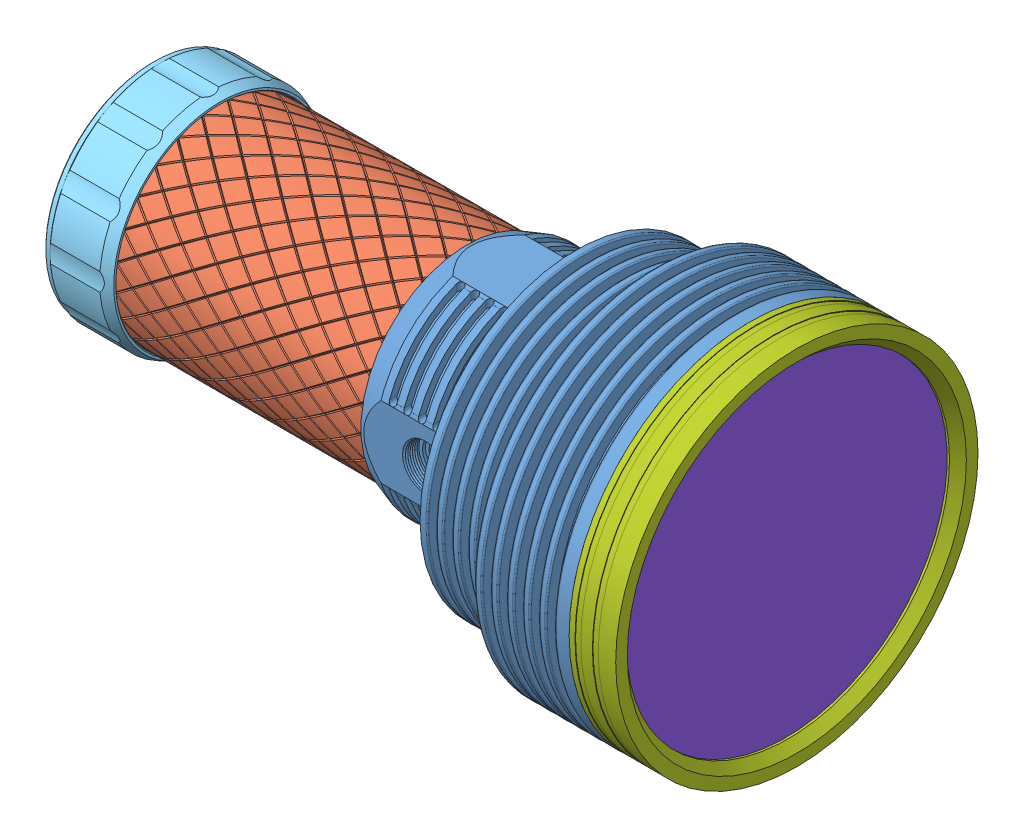
SolidWorks assembly 装配效果, configuration 默认. Lengths in mm.
Overall size (221.4 127.88 124.96).
271 component instances, 41 part files, 31 mates.
Components (placement in the parent):
- 筒头.stp-1: 筒头.stp [默认] at (76.9357 7.8194 125.8618) size (110.07 125.86 124.6)
- 筒身组件.stp-1: 筒身组件.stp [默认] at (-118.9643 -77.3753 22.2057) x (0 0 1) z (-1 0 0) size (71.18 73.16 116.38)
- 电池仓前盖.stp-1: 电池仓前盖.stp [默认] at (-20.4643 7.8194 125.8618) x (0 -1 0) z (1 0 0) size (68 69.4 6)
- 电池仓尾部显示面板.stp-1: 电池仓尾部显示面板.stp [默认] at (-9.4643 7.8194 125.8618) x (0 0 1) z (-1 0 0) size (66.2 66.2 8.5)
- 电池仓尾盖.stp-1: 电池仓尾盖.stp [默认] at (-119.4643 7.8194 125.8618) x (0 0 1) z (-1 0 0) size (76.61 76.61 23)
- SD12反光杯.stp-1: SD12反光杯.stp [默认] at (76.8857 7.8194 125.8618) size (60.57 118 118)
- 驱动仓玻璃压环.prt-1: 驱动仓玻璃压环.prt [默认] at (76.9357 7.8194 125.8618) size (18.46 127.88 124.96)
- 远射炮玻璃-1: 远射炮玻璃 [默认] at (80.8857 7.8194 125.8618) x (0 0 1) z (-1 0 0) size (118 118 4)
- 驱动压环.prt-1: 驱动压环.prt [默认] at (76.7354 7.8194 125.8618) size (7.5 56.14 54.2)
- LCD屏幕保护窗.step-1: LCD屏幕保护窗.step [默认] at (-17.9643 7.8194 125.8618) x (0 0 1) z (-1 0 0) size (26.1 15.2 2.5)
- 驱动.step-1: 驱动.step [默认] at (-8.5643 -72.1806 205.8618) x (0 0 -1) z (1 0 0) size (46.93 46.93 12.66)
  - U3.step-1: U3.step [默认] at origin size (3 1.4 1.05)
    - 549114896.step-1: 549114896.step [默认] at (69.342 72.263 -2.7003) size (3 1.4 1.05)
      - Extruded.step-1: Extruded.step [默认] at origin size (3 1.4 1.05)
  - C55.step-1: C55.step [默认] at origin size (1.6 0.8 0.3)
    - User_Library-0603_SMD_Capacitor.step-1: User_Library-0603_SMD_Capacitor.step [默认] at (69.342 69.469 -1.6003) x (-1 0 0) z (0 -1 0) size (1.6 0.3 0.8)
  - C54.step-1: C54.step [默认] at origin size (1.61 3.21 0.95)
    - User_Library-C_SMD_1206.step-1: User_Library-C_SMD_1206.step [默认] at (84.328 97.663 0) x (0 -1 0) z (0 0 1) size (3.21 1.61 0.95)
  - C53.step-1: C53.step [默认] at origin size (1.61 3.21 0.95)
    - User_Library-C_SMD_1206.step-1: User_Library-C_SMD_1206.step [默认] at (82.296 97.663 0) x (0 -1 0) z (0 0 1) size (3.21 1.61 0.95)
  - C52.step-1: C52.step [默认] at origin size (1.61 3.21 0.95)
    - User_Library-C_SMD_1206.step-1: User_Library-C_SMD_1206.step [默认] at (80.264 97.663 0) x (0 -1 0) z (0 0 1) size (3.21 1.61 0.95)
  - C51.step-1: C51.step [默认] at origin size (1.61 3.21 0.95)
    - User_Library-C_SMD_1206.step-1: User_Library-C_SMD_1206.step [默认] at (78.232 97.663 0) x (0 -1 0) z (0 0 1) size (3.21 1.61 0.95)
  - C50.step-1: C50.step [默认] at origin size (1.61 3.21 0.95)
    - User_Library-C_SMD_1206.step-1: User_Library-C_SMD_1206.step [默认] at (76.2 97.663 0) x (0 -1 0) z (0 0 1) size (3.21 1.61 0.95)
  - L1.step-1: L1.step [默认] at origin size (16.51 15.24 7.95)
    - 549113872.step-1: 549113872.step [默认] at (92.075 79.883 0.05) size (16.51 15.24 7.95)
      - Extruded-0.step-1: Extruded-0.step [默认] at origin size (16.51 15.24 7.95)
  - L2.step-1: L2.step [默认] at origin size (16.51 15.24 7.95)
    - 549113872.step-1: 549113872.step [默认] at (67.945 79.883 0.05) size (16.51 15.24 7.95)
      - Extruded-0.step-1: Extruded-0.step [默认] at origin size (16.51 15.24 7.95)
  - Q1.step-1: Q1.step [默认] at origin size (5.08 6.1 0.7)
    - 549114000.step-1: 549114000.step [默认] at (66.294 91.059 0.05) size (5.08 6.1 0.7)
      - Extruded-1.step-1: Extruded-1.step [默认] at origin size (5.08 6.1 0.7)
  - Q2.step-1: Q2.step [默认] at origin size (5.08 6.1 0.7)
    - 549114000.step-1: 549114000.step [默认] at (72.136 91.059 0.05) size (5.08 6.1 0.7)
      - Extruded-1.step-1: Extruded-1.step [默认] at origin size (5.08 6.1 0.7)
  - Q3.step-1: Q3.step [默认] at origin size (5.08 6.1 0.7)
    - 549114000.step-1: 549114000.step [默认] at (87.757 91.059 0.05) size (5.08 6.1 0.7)
      - Extruded-1.step-1: Extruded-1.step [默认] at origin size (5.08 6.1 0.7)
  - Q4.step-1: Q4.step [默认] at origin size (5.08 6.1 0.7)
    - 549114000.step-1: 549114000.step [默认] at (93.599 91.059 0.05) size (5.08 6.1 0.7)
      - Extruded-1.step-1: Extruded-1.step [默认] at origin size (5.08 6.1 0.7)
  - U1.step-1: U1.step [默认] at origin size (5.1 4.1 0.75)
    - 549115408.step-1: 549115408.step [默认] at (80.01 63.373 -2.4003) size (5.1 4.1 0.75)
      - Extruded-2.step-1: Extruded-2.step [默认] at origin size (5.1 4.1 0.75)
  - R1.step-1: R1.step [默认] at origin size (6.48 3.17 0.95)
    - 549113744.step-1: 549113744.step [默认] at (90.7415 69.7865 0.05) size (6.48 3.17 0.95)
      - Extruded-3.step-1: Extruded-3.step [默认] at origin size (6.48 3.17 0.95)
  - R2.step-1: R2.step [默认] at origin size (6.48 3.17 0.95)
    - 549113744.step-1: 549113744.step [默认] at (69.4055 69.9135 0.05) size (6.48 3.17 0.95)
      - Extruded-3.step-1: Extruded-3.step [默认] at origin size (6.48 3.17 0.95)
  - C5.step-1: C5.step [默认] at origin size (0.6 1 0.2)
    - 0402_SMD_Capacitor.step-1: 0402_SMD_Capacitor.step [默认] at (81.915 72.6266 -1.6003) x (0 -1 0) z (1 0 0) size (1 0.2 0.6)
  - C6.step-1: C6.step [默认] at origin size (0.6 1 0.2)
    - 0402_SMD_Capacitor.step-1: 0402_SMD_Capacitor.step [默认] at (77.216 70.6294 -1.6003) x (0 1 0) z (-1 0 0) size (1 0.2 0.6)
  - C7.step-1: C7.step [默认] at origin size (0.6 1 0.2)
    - 0402_SMD_Capacitor.step-1: 0402_SMD_Capacitor.step [默认] at (80.518 67.2926 -1.6003) x (0 -1 0) z (1 0 0) size (1 0.2 0.6)
  - C8.step-1: C8.step [默认] at origin size (0.6 1 0.2)
    - 0402_SMD_Capacitor.step-1: 0402_SMD_Capacitor.step [默认] at (79.375 67.2926 -1.6003) x (0 -1 0) z (1 0 0) size (1 0.2 0.6)
  - C12.step-1: C12.step [默认] at origin size (1.68 3.4 1.71)
    - User_Library-AVX_ACASE.step-1: User_Library-AVX_ACASE.step [默认] at (86.7411 74.0411 -1.6003) x (0 1 0) z (0 0 -1) size (3.4 1.68 1.71)
  - R3.step-1: R3.step [默认] at origin size (0.55 1.15 0.41)
    - User_Library-RES_1005-0402.step-1: User_Library-RES_1005-0402.step [默认] at (77.216 72.771 -1.6003) x (0 1 0) z (-1 0 0) size (1.15 0.41 0.55)
  - R4.step-1: R4.step [默认] at origin size (1.15 0.55 0.41)
    - User_Library-RES_1005-0402.step-1: User_Library-RES_1005-0402.step [默认] at (81.026 69.088 -1.6003) x (-1 0 0) z (0 -1 0) size (1.15 0.41 0.55)
  - R5.step-1: R5.step [默认] at origin size (1.15 0.55 0.41)
    - User_Library-RES_1005-0402.step-1: User_Library-RES_1005-0402.step [默认] at (78.867 69.088 -1.6003) x (-1 0 0) z (0 -1 0) size (1.15 0.41 0.55)
  - U2.step-1: U2.step [默认] at origin size (3 1.4 1.05)
    - 549114896.step-1: 549114896.step [默认] at (79.629 71.882 -2.7003) size (3 1.4 1.05)
      - Extruded.step-1: Extruded.step [默认] at origin size (3 1.4 1.05)
  - L3.step-1: L3.step [默认] at origin size (1.91 2.03 3.01)
    - 549110928.step-1: 549110928.step [默认] at (84.0105 72.771 -4.6603) size (1.91 2.03 3.01)
      - Extruded-4.step-1: Extruded-4.step [默认] at origin size (1.91 2.03 3.01)
  - C9.step-1: C9.step [默认] at origin size (0.6 1 0.2)
    - 0402_SMD_Capacitor.step-1: 0402_SMD_Capacitor.step [默认] at (77.851 67.3274 -1.6003) x (0 1 0) z (-1 0 0) size (1 0.2 0.6)
  - D1.step-1: D1.step [默认] at origin size (2.7 1.25 1.1)
    - SOD323.step-1: SOD323.step [默认] at (78.613 65.151 0) x (1 0 0) z (0 0 1) size (2.7 1.25 1.1)
  - C10.step-1: C10.step [默认] at origin size (0.6 1 0.2)
    - 0402_SMD_Capacitor.step-1: 0402_SMD_Capacitor.step [默认] at (82.169 67.3274 -1.6003) x (0 1 0) z (-1 0 0) size (1 0.2 0.6)
  - D2.step-1: D2.step [默认] at origin size (2.7 1.25 1.1)
    - SOD323.step-1: SOD323.step [默认] at (82.296 65.151 0) x (-1 0 0) z (0 0 1) size (2.7 1.25 1.1)
  - C11.step-1: C11.step [默认] at origin size (1.61 3.21 0.95)
    - User_Library-C_SMD_1206.step-1: User_Library-C_SMD_1206.step [默认] at (80.899 85.09 0) x (0 -1 0) z (0 0 1) size (3.21 1.61 0.95)
  - C13.step-1: C13.step [默认] at origin size (1.61 3.21 0.95)
    - User_Library-C_SMD_1206.step-1: User_Library-C_SMD_1206.step [默认] at (79.121 85.09 0) x (0 -1 0) z (0 0 1) size (3.21 1.61 0.95)
  - C14.step-1: C14.step [默认] at origin size (1.61 3.21 0.95)
    - User_Library-C_SMD_1206.step-1: User_Library-C_SMD_1206.step [默认] at (77.343 85.09 0) x (0 -1 0) z (0 0 1) size (3.21 1.61 0.95)
  - C15.step-1: C15.step [默认] at origin size (1.61 3.21 0.95)
    - User_Library-C_SMD_1206.step-1: User_Library-C_SMD_1206.step [默认] at (82.677 85.09 0) x (0 -1 0) z (0 0 1) size (3.21 1.61 0.95)
  - C16.step-1: C16.step [默认] at origin size (1.61 3.21 0.95)
    - User_Library-C_SMD_1206.step-1: User_Library-C_SMD_1206.step [默认] at (72.009 97.536 0) x (0 -1 0) z (0 0 1) size (3.21 1.61 0.95)
  - C17.step-1: C17.step [默认] at origin size (1.61 3.21 0.95)
    - User_Library-C_SMD_1206.step-1: User_Library-C_SMD_1206.step [默认] at (87.376 97.663 0) x (0 -1 0) z (0 0 1) size (3.21 1.61 0.95)
  - C18.step-1: C18.step [默认] at origin size (1.61 3.21 0.95)
    - User_Library-C_SMD_1206.step-1: User_Library-C_SMD_1206.step [默认] at (80.264 97.663 -1.6003) x (0 -1 0) z (0 0 -1) size (3.21 1.61 0.95)
  - C19.step-1: C19.step [默认] at origin size (1.61 3.21 0.95)
    - User_Library-C_SMD_1206.step-1: User_Library-C_SMD_1206.step [默认] at (76.2 97.663 -1.6003) x (0 -1 0) z (0 0 -1) size (3.21 1.61 0.95)
  - C20.step-1: C20.step [默认] at origin size (1.61 3.21 0.95)
    - User_Library-C_SMD_1206.step-1: User_Library-C_SMD_1206.step [默认] at (84.328 97.663 -1.6003) x (0 -1 0) z (0 0 -1) size (3.21 1.61 0.95)
  - C21.step-1: C21.step [默认] at origin size (1.61 3.21 0.95)
    - User_Library-C_SMD_1206.step-1: User_Library-C_SMD_1206.step [默认] at (82.296 97.663 -1.6003) x (0 -1 0) z (0 0 -1) size (3.21 1.61 0.95)
  - C22.step-1: C22.step [默认] at origin size (3.21 1.61 0.95)
    - User_Library-C_SMD_1206.step-1: User_Library-C_SMD_1206.step [默认] at (70.485 95.885 -1.6003) x (1 0 0) z (0 0 -1) size (3.21 1.61 0.95)
  - C23.step-1: C23.step [默认] at origin size (3.21 1.61 0.95)
    - User_Library-C_SMD_1206.step-1: User_Library-C_SMD_1206.step [默认] at (88.646 96.012 -1.6003) x (-1 0 0) z (0 0 -1) size (3.21 1.61 0.95)
  - C24.step-1: C24.step [默认] at origin size (1.61 3.21 0.95)
    - User_Library-C_SMD_1206.step-1: User_Library-C_SMD_1206.step [默认] at (78.232 97.663 -1.6003) x (0 -1 0) z (0 0 -1) size (3.21 1.61 0.95)
  - C25.step-1: C25.step [默认] at origin size (1.61 3.21 0.95)
    - User_Library-C_SMD_1206.step-1: User_Library-C_SMD_1206.step [默认] at (77.978 89.535 -1.6003) x (0 -1 0) z (0 0 -1) size (3.21 1.61 0.95)
  - C26.step-1: C26.step [默认] at origin size (1.61 3.21 0.95)
    - User_Library-C_SMD_1206.step-1: User_Library-C_SMD_1206.step [默认] at (80.137 89.535 -1.6003) x (0 -1 0) z (0 0 -1) size (3.21 1.61 0.95)
  - C27.step-1: C27.step [默认] at origin size (1.61 3.21 0.95)
    - User_Library-C_SMD_1206.step-1: User_Library-C_SMD_1206.step [默认] at (75.819 89.535 -1.6003) x (0 -1 0) z (0 0 -1) size (3.21 1.61 0.95)
  - C28.step-1: C28.step [默认] at origin size (1.61 3.21 0.95)
    - User_Library-C_SMD_1206.step-1: User_Library-C_SMD_1206.step [默认] at (86.741 68.453 -1.6003) x (0 1 0) z (0 0 -1) size (3.21 1.61 0.95)
  - C29.step-1: C29.step [默认] at origin size (1.61 3.21 0.95)
    - User_Library-C_SMD_1206.step-1: User_Library-C_SMD_1206.step [默认] at (84.201 89.535 -1.6003) x (0 -1 0) z (0 0 -1) size (3.21 1.61 0.95)
  - C30.step-1: C30.step [默认] at origin size (1.61 3.21 0.95)
    - User_Library-C_SMD_1206.step-1: User_Library-C_SMD_1206.step [默认] at (82.169 89.535 -1.6003) x (0 -1 0) z (0 0 -1) size (3.21 1.61 0.95)
  - C31.step-1: C31.step [默认] at origin size (1 0.6 0.2)
    - 0402_SMD_Capacitor.step-1: 0402_SMD_Capacitor.step [默认] at (74.9474 65.659 -1.6003) x (1 0 0) z (0 1 0) size (1 0.2 0.6)
  - C32.step-1: C32.step [默认] at origin size (1 0.6 0.2)
    - 0402_SMD_Capacitor.step-1: 0402_SMD_Capacitor.step [默认] at (74.9474 63.373 -1.6003) x (1 0 0) z (0 1 0) size (1 0.2 0.6)
  - R6.step-1: R6.step [默认] at origin size (1.15 0.55 0.41)
    - User_Library-RES_1005-0402.step-1: User_Library-RES_1005-0402.step [默认] at (74.93 61.087 -1.6003) x (-1 0 0) z (0 -1 0) size (1.15 0.41 0.55)
  - R7.step-1: R7.step [默认] at origin size (1.15 0.55 0.41)
    - User_Library-RES_1005-0402.step-1: User_Library-RES_1005-0402.step [默认] at (74.93 64.516 -1.6003) x (-1 0 0) z (0 -1 0) size (1.15 0.41 0.55)
  - R8.step-1: R8.step [默认] at origin size (1.15 0.55 0.41)
    - User_Library-RES_1005-0402.step-1: User_Library-RES_1005-0402.step [默认] at (74.93 62.23 -1.6003) x (-1 0 0) z (0 -1 0) size (1.15 0.41 0.55)
  - C33.step-1: C33.step [默认] at origin size (1 0.6 0.2)
    - 0402_SMD_Capacitor.step-1: 0402_SMD_Capacitor.step [默认] at (77.1986 60.071 -1.6003) x (-1 0 0) z (0 -1 0) size (1 0.2 0.6)
  - R9.step-1: R9.step [默认] at origin size (0.55 1.15 0.41)
    - User_Library-RES_1005-0402.step-1: User_Library-RES_1005-0402.step [默认] at (83.566 60.706 -1.6003) x (0 -1 0) z (1 0 0) size (1.15 0.41 0.55)
  - R10.step-1: R10.step [默认] at origin size (1.15 0.55 0.41)
    - User_Library-RES_1005-0402.step-1: User_Library-RES_1005-0402.step [默认] at (79.375 59.817 -1.6003) x (-1 0 0) z (0 -1 0) size (1.15 0.41 0.55)
  - R11.step-1: R11.step [默认] at origin size (1.15 0.55 0.41)
    - User_Library-RES_1005-0402.step-1: User_Library-RES_1005-0402.step [默认] at (81.407 60.071 -1.6003) x (-1 0 0) z (0 -1 0) size (1.15 0.41 0.55)
  - C34.step-1: C34.step [默认] at origin size (1.6 0.8 0.3)
    - User_Library-0603_SMD_Capacitor.step-1: User_Library-0603_SMD_Capacitor.step [默认] at (70.485 84.074 -1.6003) x (1 0 0) z (0 1 0) size (1.6 0.3 0.8)
  - C35.step-1: C35.step [默认] at origin size (1 0.6 0.2)
    - 0402_SMD_Capacitor.step-1: 0402_SMD_Capacitor.step [默认] at (70.3754 78.486 -1.6003) x (1 0 0) z (0 1 0) size (1 0.2 0.6)
  - FB1.step-1: FB1.step [默认] at origin size (1.09 0.53 0.38)
    - L0402.step-1: L0402.step [默认] at (70.3453 77.089 -1.6003) x (-1 0 0) z (0 0 -1) size (1.09 0.53 0.38)
  - U4.step-1: U4.step [默认] at origin size (3 1.4 1.05)
    - 549114896.step-1: 549114896.step [默认] at (70.485 81.153 -2.7003) size (3 1.4 1.05)
      - Extruded.step-1: Extruded.step [默认] at origin size (3 1.4 1.05)
  - Q5.step-1: Q5.step [默认] at origin size (5.1 6.1 1)
    - 549115152.step-1: 549115152.step [默认] at (64.643 73.025 -2.6503) size (5.1 6.1 1)
      - Extruded-5.step-1: Extruded-5.step [默认] at origin size (5.1 6.1 1)
  - R12.step-1: R12.step [默认] at origin size (0.55 1.15 0.41)
    - User_Library-RES_1005-0402.step-1: User_Library-RES_1005-0402.step [默认] at (66.929 77.978 -1.6003) x (0 1 0) z (-1 0 0) size (1.15 0.41 0.55)
  - R13.step-1: R13.step [默认] at origin size (3.17 6.48 0.95)
    - 549111056.step-1: 549111056.step [默认] at (63.9445 81.2165 -2.6003) size (3.17 6.48 0.95)
      - Extruded-6.step-1: Extruded-6.step [默认] at origin size (3.17 6.48 0.95)
  - C36.step-1: C36.step [默认] at origin size (0.6 1 0.2)
    - 0402_SMD_Capacitor.step-1: 0402_SMD_Capacitor.step [默认] at (74.676 64.6604 0) x (0 1 0) z (1 0 0) size (1 0.2 0.6)
  - U5.step-1: U5.step [默认] at origin size (1.35 2.2 1)
    - 549114128.step-1: 549114128.step [默认] at (71.628 62.484 0.1) size (1.35 2.2 1)
      - Extruded-7.step-1: Extruded-7.step [默认] at origin size (1.35 2.2 1)
  - C37.step-1: C37.step [默认] at origin size (0.6 1 0.2)
    - 0402_SMD_Capacitor.step-1: 0402_SMD_Capacitor.step [默认] at (82.296 61.4506 0) x (0 -1 0) z (-1 0 0) size (1 0.2 0.6)
  - C38.step-1: C38.step [默认] at origin size (0.6 1 0.2)
    - 0402_SMD_Capacitor.step-1: 0402_SMD_Capacitor.step [默认] at (76.073 63.3556 0) x (0 -1 0) z (-1 0 0) size (1 0.2 0.6)
  - R15.step-1: R15.step [默认] at origin size (1.15 0.55 0.41)
    - User_Library-RES_1005-0402.step-1: User_Library-RES_1005-0402.step [默认] at (84.074 61.214 0) x (-1 0 0) z (0 1 0) size (1.15 0.41 0.55)
  - R16.step-1: R16.step [默认] at origin size (0.55 1.15 0.41)
    - User_Library-RES_1005-0402.step-1: User_Library-RES_1005-0402.step [默认] at (80.899 61.468 0) x (0 -1 0) z (-1 0 0) size (1.15 0.41 0.55)
  - U6.step-1: U6.step [默认] at origin size (3 1.4 1.05)
    - 549114896.step-1: 549114896.step [默认] at (78.486 62.738 0.05) size (3 1.4 1.05)
      - Extruded.step-1: Extruded.step [默认] at origin size (3 1.4 1.05)
  - R17.step-1: R17.step [默认] at origin size (1.15 0.55 0.41)
    - User_Library-RES_1005-0402.step-1: User_Library-RES_1005-0402.step [默认] at (75.184 61.595 0) x (-1 0 0) z (0 1 0) size (1.15 0.41 0.55)
  - C39.step-1: C39.step [默认] at origin size (0.8 1.6 0.3)
    - User_Library-0603_SMD_Capacitor.step-1: User_Library-0603_SMD_Capacitor.step [默认] at (92.456 85.598 -1.6003) x (0 -1 0) z (1 0 0) size (1.6 0.3 0.8)
  - C40.step-1: C40.step [默认] at origin size (0.6 1 0.2)
    - 0402_SMD_Capacitor.step-1: 0402_SMD_Capacitor.step [默认] at (86.868 86.0886 -1.6003) x (0 -1 0) z (1 0 0) size (1 0.2 0.6)
  - FB2.step-1: FB2.step [默认] at origin size (0.53 1.09 0.38)
    - L0402.step-1: L0402.step [默认] at (86.868 83.8327 -1.6003) x (0 1 0) z (0 0 -1) size (1.09 0.53 0.38)
  - U7.step-1: U7.step [默认] at origin size (1.4 3 1.05)
    - 549114768.step-1: 549114768.step [默认] at (89.535 85.598 -2.7003) size (1.4 3 1.05)
      - Extruded-8.step-1: Extruded-8.step [默认] at origin size (1.4 3 1.05)
  - C41.step-1: C41.step [默认] at origin size (1 0.6 0.2)
    - 0402_SMD_Capacitor.step-1: 0402_SMD_Capacitor.step [默认] at (94.8864 83.312 -1.6003) x (1 0 0) z (0 1 0) size (1 0.2 0.6)
  - U8.step-1: U8.step [默认] at origin size (3.1 3.1 0.75)
    - 549114512.step-1: 549114512.step [默认] at (94.488 80.137 -2.4003) size (3.1 3.1 0.75)
      - Extruded-9.step-1: Extruded-9.step [默认] at origin size (3.1 3.1 0.75)
  - D3.step-1: D3.step [默认] at origin size (1.25 2.7 1.1)
    - SOD323.step-1: SOD323.step [默认] at (86.868 78.613 -1.6003) x (0 -1 0) z (0 0 -1) size (2.7 1.25 1.1)
  - R20.step-1: R20.step [默认] at origin size (0.55 1.15 0.41)
    - User_Library-RES_1005-0402.step-1: User_Library-RES_1005-0402.step [默认] at (86.868 81.661 -1.6003) x (0 1 0) z (-1 0 0) size (1.15 0.41 0.55)
  - R21.step-1: R21.step [默认] at origin size (0.55 1.15 0.41)
    - User_Library-RES_1005-0402.step-1: User_Library-RES_1005-0402.step [默认] at (91.186 81.661 -1.6003) x (0 1 0) z (-1 0 0) size (1.15 0.41 0.55)
  - R22.step-1: R22.step [默认] at origin size (0.55 1.15 0.41)
    - User_Library-RES_1005-0402.step-1: User_Library-RES_1005-0402.step [默认] at (88.392 81.661 -1.6003) x (0 -1 0) z (1 0 0) size (1.15 0.41 0.55)
  - R23.step-1: R23.step [默认] at origin size (0.55 1.15 0.41)
    - User_Library-RES_1005-0402.step-1: User_Library-RES_1005-0402.step [默认] at (89.789 81.661 -1.6003) x (0 -1 0) z (1 0 0) size (1.15 0.41 0.55)
  - R19.step-1: R19.step [默认] at origin size (0.55 1.15 0.41)
    - User_Library-RES_1005-0402.step-1: User_Library-RES_1005-0402.step [默认] at (88.392 79.375 -1.6003) x (0 -1 0) z (1 0 0) size (1.15 0.41 0.55)
  - C42.step-1: C42.step [默认] at origin size (1.25 2 0.78)
    - User_Library-0805_SMD_Capacitor.step-1: User_Library-0805_SMD_Capacitor.step [默认] at (89.154 74.1675 -1.5903) x (0 -1 0) z (1 0 0) size (2 0.78 1.25)
  - C44.step-1: C44.step [默认] at origin size (1 0.6 0.2)
    - 0402_SMD_Capacitor.step-1: 0402_SMD_Capacitor.step [默认] at (87.9014 66.929 0) x (1 0 0) z (0 -1 0) size (1 0.2 0.6)
  - C45.step-1: C45.step [默认] at origin size (0.6 1 0.2)
    - 0402_SMD_Capacitor.step-1: 0402_SMD_Capacitor.step [默认] at (86.868 65.1336 0) x (0 -1 0) z (-1 0 0) size (1 0.2 0.6)
  - D4.step-1: D4.step [默认] at origin size (1.35 2.2 1)
    - 549114128.step-1: 549114128.step [默认] at (87.884 64.389 -2.7003) size (1.35 2.2 1)
      - Extruded-7.step-1: Extruded-7.step [默认] at origin size (1.35 2.2 1)
  - R24.step-1: R24.step [默认] at origin size (0.55 1.15 0.41)
    - User_Library-RES_1005-0402.step-1: User_Library-RES_1005-0402.step [默认] at (89.662 66.548 0) x (0 -1 0) z (-1 0 0) size (1.15 0.41 0.55)
  - R25.step-1: R25.step [默认] at origin size (0.55 1.15 0.41)
    - User_Library-RES_1005-0402.step-1: User_Library-RES_1005-0402.step [默认] at (88.265 65.151 0) x (0 -1 0) z (-1 0 0) size (1.15 0.41 0.55)
  - U9.step-1: U9.step [默认] at origin size (2.2 1.35 1)
    - 549114384.step-1: 549114384.step [默认] at (86.36 62.357 0.1) size (2.2 1.35 1)
      - Extruded-10.step-1: Extruded-10.step [默认] at origin size (2.2 1.35 1)
  - C43.step-1: C43.step [默认] at origin size (0.6 1 0.2)
    - 0402_SMD_Capacitor.step-1: 0402_SMD_Capacitor.step [默认] at (88.265 61.9586 0) x (0 -1 0) z (-1 0 0) size (1 0.2 0.6)
  - R26.step-1: R26.step [默认] at origin size (1.15 0.55 0.41)
    - User_Library-RES_1005-0402.step-1: User_Library-RES_1005-0402.step [默认] at (90.678 77.597 -1.6003) x (-1 0 0) z (0 -1 0) size (1.15 0.41 0.55)
  - U10.step-1: U10.step [默认] at origin size (1.35 2.2 1)
    - 549114128.step-1: 549114128.step [默认] at (94.615 76.073 -2.7003) size (1.35 2.2 1)
      - Extruded-7.step-1: Extruded-7.step [默认] at origin size (1.35 2.2 1)
  - R27.step-1: R27.step [默认] at origin size (0.55 1.15 0.41)
    - User_Library-RES_1005-0402.step-1: User_Library-RES_1005-0402.step [默认] at (97.536 76.073 -1.6003) x (0 1 0) z (-1 0 0) size (1.15 0.41 0.55)
  - C46.step-1: C46.step [默认] at origin size (0.6 1 0.2)
    - 0402_SMD_Capacitor.step-1: 0402_SMD_Capacitor.step [默认] at (97.536 78.7226 -1.6003) x (0 -1 0) z (1 0 0) size (1 0.2 0.6)
  - R28.step-1: R28.step [默认] at origin size (1.15 0.55 0.41)
    - User_Library-RES_1005-0402.step-1: User_Library-RES_1005-0402.step [默认] at (82.169 59.436 0) x (1 0 0) z (0 -1 0) size (1.15 0.41 0.55)
  - C47.step-1: C47.step [默认] at origin size (0.6 1 0.2)
    - 0402_SMD_Capacitor.step-1: 0402_SMD_Capacitor.step [默认] at (97.536 83.2946 -1.6003) x (0 -1 0) z (1 0 0) size (1 0.2 0.6)
  - R29.step-1: R29.step [默认] at origin size (0.55 1.15 0.41)
    - User_Library-RES_1005-0402.step-1: User_Library-RES_1005-0402.step [默认] at (97.536 81.026 -1.6003) x (0 -1 0) z (1 0 0) size (1.15 0.41 0.55)
  - R30.step-1: R30.step [默认] at origin size (1.7 0.8 0.56)
    - User_Library-RES_1609-0603.step-1: User_Library-RES_1609-0603.step [默认] at (95.377 86.233 -1.6003) x (1 0 0) z (0 1 0) size (1.7 0.56 0.8)
  - C48.step-1: C48.step [默认] at origin size (0.8 1.6 0.3)
    - User_Library-0603_SMD_Capacitor.step-1: User_Library-0603_SMD_Capacitor.step [默认] at (78.486 68.707 0) x (0 1 0) z (1 0 0) size (1.6 0.3 0.8)
  - C49.step-1: C49.step [默认] at origin size (0.8 1.6 0.3)
    - User_Library-0603_SMD_Capacitor.step-1: User_Library-0603_SMD_Capacitor.step [默认] at (81.661 68.707 0) x (0 1 0) z (1 0 0) size (1.6 0.3 0.8)
  - R14.step-1: R14.step [默认] at origin size (1.15 0.55 0.41)
    - User_Library-RES_1005-0402.step-1: User_Library-RES_1005-0402.step [默认] at (75.184 59.563 0) x (1 0 0) z (0 -1 0) size (1.15 0.41 0.55)
  - D5.step-1: D5.step [默认] at origin size (1.02 1.14 0.95)
    - 549111568.step-1: 549111568.step [默认] at (96.139 73.6385 -2.6003) size (1.02 1.14 0.95)
      - Extruded-11.step-1: Extruded-11.step [默认] at origin size (1.02 1.14 0.95)
  - R31.step-1: R31.step [默认] at origin size (0.55 1.15 0.41)
    - User_Library-RES_1005-0402.step-1: User_Library-RES_1005-0402.step [默认] at (97.536 73.533 -1.6003) x (0 1 0) z (-1 0 0) size (1.15 0.41 0.55)
  - U11.step-1: U11.step [默认] at origin size (1.35 2.2 1)
    - 549114128.step-1: 549114128.step [默认] at (71.628 65.278 0.1) size (1.35 2.2 1)
      - Extruded-7.step-1: Extruded-7.step [默认] at origin size (1.35 2.2 1)
  - R18.step-1: R18.step [默认] at origin size (1.15 0.55 0.41)
    - User_Library-RES_1005-0402.step-1: User_Library-RES_1005-0402.step [默认] at (92.837 83.312 -1.6003) x (1 0 0) z (0 1 0) size (1.15 0.41 0.55)
  - C56.step-1: C56.step [默认] at origin size (0.6 1 0.2)
    - 0402_SMD_Capacitor.step-1: 0402_SMD_Capacitor.step [默认] at (72.644 65.1336 -1.6003) x (0 -1 0) z (1 0 0) size (1 0.2 0.6)
  - R32.step-1: R32.step [默认] at origin size (0.55 1.15 0.41)
    - User_Library-RES_1005-0402.step-1: User_Library-RES_1005-0402.step [默认] at (72.644 62.865 -1.6003) x (0 -1 0) z (1 0 0) size (1.15 0.41 0.55)
  - C57.step-1: C57.step [默认] at origin size (1.61 3.21 0.95)
    - User_Library-C_SMD_1206.step-1: User_Library-C_SMD_1206.step [默认] at (73.787 69.596 -1.6003) x (0 1 0) z (0 0 -1) size (3.21 1.61 0.95)
  - Free-Models.step-1: Free-Models.step [默认] at origin size (32.13 22.61 3.6)
    - 549111184.step-1: 549111184.step [默认] at (69.0245 90.551 -2.6003) size (10.03 4.06 0.95)
      - Extruded-12.step-1: Extruded-12.step [默认] at origin size (10.03 4.06 0.95)
    - 549111312.step-1: 549111312.step [默认] at (91.1225 90.551 -2.6003) size (10.03 3.94 0.95)
      - Extruded-13.step-1: Extruded-13.step [默认] at origin size (10.03 3.94 0.95)
    - 549111440.step-1: 549111440.step [默认] at (79.9465 89.662 0.05) size (8 3.05 0.95)
      - Extruded-14.step-1: Extruded-14.step [默认] at origin size (8 3.05 0.95)
    - 549111696.step-1: 549111696.step [默认] at (80.01 76.2635 0.05) size (6.1 12.57 0.95)
      - Extruded-15.step-1: Extruded-15.step [默认] at origin size (6.1 12.57 0.95)
  - Board.step-1: Board.step [默认] at (0 0 -1.6003) size (46.93 46.93 1.6)
- 电池架.step-1: 电池架.step [默认] at (-14.4643 7.8194 125.8618) x (0 0 1) z (-1 0 0) size (65.4 65.4 108.9)
- 电池正极铜垫片-1: 电池正极铜垫片 [默认] at (-21.4643 7.8194 125.8618) x (0 0 -1) z (1 0 0) size (35.6 35.6 4.5)
- 电池架正极黄铜导电电极-1: 电池架正极黄铜导电电极 [默认] at (-16.0643 7.8194 125.8618) x (0 0 1) z (-1 0 0) size (15 15 18.3)
- 驱动散热铜块-1: 驱动散热铜块 [默认] at (1.4357 -72.1806 205.8618) x (0 0 -1) z (1 0 0) size (40.51 21.72 8.1)
Mates (geometry in assembly coordinates):
- 重合1: coincident anti-aligned: plane of 筒头.stp-1 through (-14.4643 42.3194 125.8618) normal (-1 0 0); plane of 筒身组件.stp-1 through (-14.4643 7.8194 125.8618) normal (1 0 0)
- 同心1: concentric anti-aligned: circle of 筒头.stp-1; circle of 筒身组件.stp-1
- 重合7: coincident anti-aligned: plane of 筒身组件.stp-1 through (-126.9643 7.8194 111.3618) normal (-1 0 0); plane of 电池仓尾部显示面板.stp-1 through (-126.9643 7.8194 125.8618) normal (1 0 0)
- 重合8: coincident aligned: circle of 筒身组件.stp-1; circle of 电池仓尾部显示面板.stp-1
- 同心2: concentric aligned: circle of 筒身组件.stp-1; circle of 电池仓尾部显示面板.stp-1
- 重合9: coincident anti-aligned: plane of 筒身组件.stp-1 through (-129.4643 7.8194 125.8618) normal (-1 0 0); plane of 电池仓尾盖.stp-1 through (-129.4643 42.3194 125.8618) normal (1 0 0)
- 同心3: concentric anti-aligned: circle of 筒身组件.stp-1; circle of 电池仓尾盖.stp-1
- 同心6: concentric aligned: circle of 筒身组件.stp-1; circle of 电池仓前盖.stp-1
- 同心7: concentric anti-aligned: circle of 筒身组件.stp-1; circle of 电池仓前盖.stp-1
- 重合12: coincident anti-aligned: plane of 筒头.stp-1 through (72.3857 64.8194 125.8618) normal (1 0 0); plane of SD12反光杯.stp-1 through (72.3857 -50.3806 125.8618) normal (-1 0 0)
- 同心8: concentric anti-aligned: circle of 筒头.stp-1; circle of SD12反光杯.stp-1
- 重合13: coincident anti-aligned: plane of 筒头.stp-1 through (68.9357 67.9194 125.8618) normal (1 0 0); plane of 驱动仓玻璃压环.prt-1 through (68.9357 7.8194 64.5618) normal (-1 0 0)
- 同心9: concentric aligned: circle of 筒头.stp-1; circle of 驱动仓玻璃压环.prt-1
- 重合15: coincident anti-aligned: plane of SD12反光杯.stp-1 through (76.8857 7.8194 125.8618) normal (1 0 0); plane of 远射炮玻璃-1 through (76.8857 7.8194 125.8618) normal (-1 0 0)
- 同心10: concentric anti-aligned: circle of 驱动仓玻璃压环.prt-1; circle of 远射炮玻璃-1
- 同心11: concentric aligned: circle of 筒头.stp-1; circle of 驱动压环.prt-1
- 重合17: coincident anti-aligned: plane of 电池仓尾部显示面板.stp-1 through (-127.9643 7.1898 116.1526) normal (1 0 0); plane of LCD屏幕保护窗.step-1 through (-127.9643 7.3901 138.0529) normal (-1 0 0)
- 重合18: coincident aligned: line of 电池仓尾部显示面板.stp-1 through (-129.4643 18.0202 138.8029) axis (0 -1 0); line of LCD屏幕保护窗.step-1 through (-129.4643 18.1901 138.8029) axis (0 -1 0)
- 重合19: coincident aligned: line of 电池仓尾部显示面板.stp-1 through (-129.4643 18.9401 116.5228) axis (0 0 1); line of LCD屏幕保护窗.step-1 through (-129.4643 18.9401 116.3529) axis (0 0 1)
- 重合20: coincident anti-aligned: plane of 筒头.stp-1 through (-8.5643 31.4194 125.8618) normal (-1 0 0); plane of 驱动.step-1/Board.step-1 through (-8.5643 -15.5929 124.3272) normal (1 0 0)
- 同心12: concentric anti-aligned: circle of 驱动.step-1/Board.step-1; circle of 筒头.stp-1
- 重合22: coincident anti-aligned: plane of 驱动压环.prt-1 through (-10.1646 28.8194 125.8618) normal (1 0 0); plane of 驱动.step-1/Board.step-1 through (-10.1646 -15.5929 124.3272) normal (-1 0 0)
- 重合23: coincident anti-aligned: plane of 电池仓前盖.stp-1 through (-20.4643 7.8194 125.8618) normal (-1 0 0); plane of 电池架.step-1 through (-20.4643 7.8194 125.8618) normal (1 0 0)
- 同心13: concentric aligned: circle of 电池仓前盖.stp-1; circle of 电池架.step-1
- 重合25: coincident anti-aligned: plane of 电池架.step-1 through (-21.4643 7.8194 125.8618) normal (1 0 0); plane of 电池正极铜垫片-1 through (-21.4643 7.8194 125.8618) normal (-1 0 0)
- 同心14: concentric anti-aligned: circle of 电池仓前盖.stp-1; circle of 电池正极铜垫片-1
- 重合26: coincident anti-aligned: plane of 电池正极铜垫片-1 through (-19.3643 7.8194 125.8618) normal (1 0 0); circle of 电池架正极黄铜导电电极-1
- 同心15: concentric aligned: circle of 电池正极铜垫片-1; circle of 电池架正极黄铜导电电极-1
- 重合27: coincident anti-aligned: plane of 驱动.step-1/L1.step-1/549113872.step-1/Extruded-0.step-1 through (-0.5643 0.0824 122.0418) normal (1 0 0); plane of 驱动散热铜块-1 through (-0.5643 -72.1806 205.8618) normal (-1 0 0)
- 重合28: coincident anti-aligned: line of 驱动.step-1/L2.step-1/549113872.step-1/Extruded-0.step-1 through (-0.5643 0.0824 146.1718) axis (0 1 0); line of 驱动散热铜块-1 through (-0.5643 15.3224 146.1718) axis (0 -1 0)
- 重合29: coincident anti-aligned: line of 驱动.step-1/L2.step-1/549113872.step-1/Extruded-0.step-1 through (-0.5643 0.0824 129.6618) axis (0 0 1); line of 驱动散热铜块-1 through (-0.5643 0.0824 146.1718) axis (0 0 -1)
